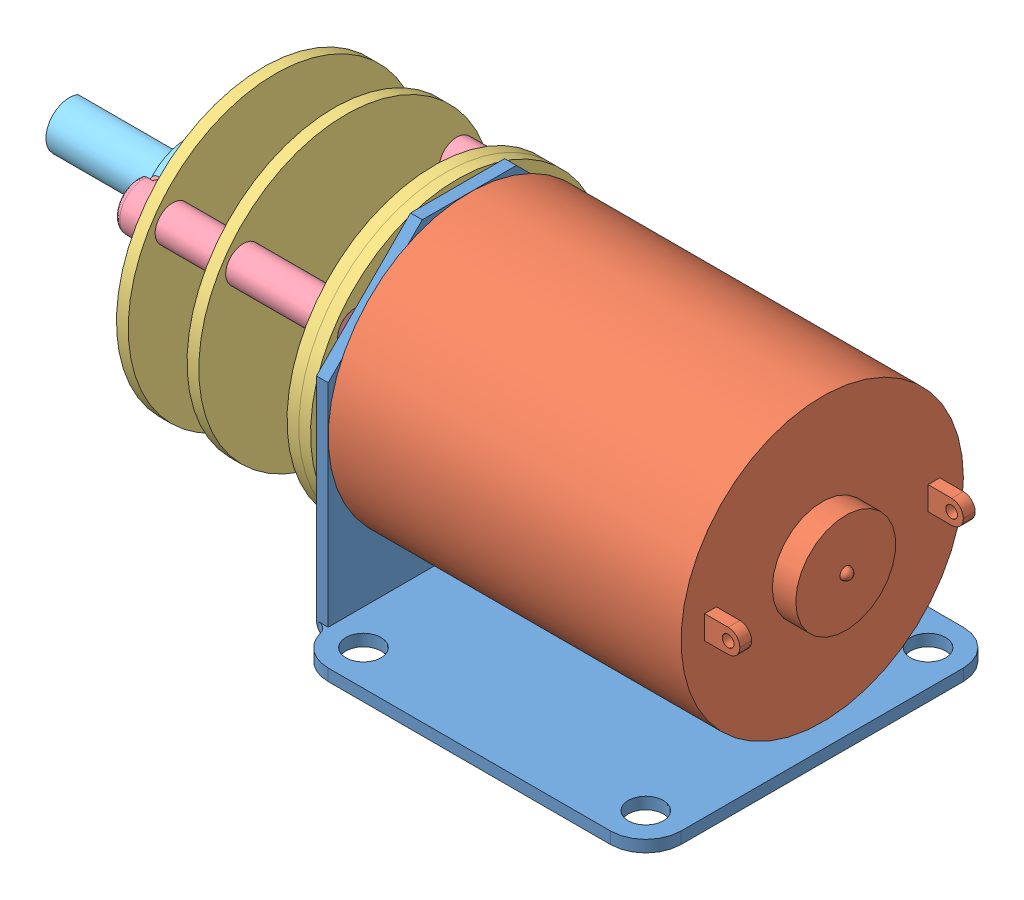
SolidWorks assembly MotorMFA, configuration Défaut. Lengths in mm.
Overall size (67 33.45 33.45).
10 component instances, 5 part files, 21 mates.
Components (placement in the parent):
- Square-1: Square [Défaut] at (-19.9694 1.8332 31) size (31 27 30)
- Body-1: Body [Défaut] at (11.0306 3.3332 31) size (33 24 24)
- Plate-1: Plate [Défaut] at (-20.9694 3.3332 31) x (1 0 0) z (0 0.898006 0.439983) size (1 25 25)
- Plate-2: Plate [Défaut] at (-21.9694 3.3332 31) x (1 0 0) z (0 0.898006 0.439983) size (1 25 25)
- Plate-3: Plate [Défaut] at (-30.4694 3.3332 31) x (1 0 0) z (0 0.898006 0.439983) size (1 25 25)
- Plate-4: Plate [Défaut] at (-36.4694 3.3332 31) x (1 0 0) z (0 0.898006 0.439983) size (1 25 25)
- Screw-4: Screw [Défaut] at (-19.9694 9.1891 39.7154) x (0 0.394119 0.91906) z (0 -0.91906 0.394119) size (4 18.53 4)
- Screw-5: Screw [Défaut] at (-19.9694 7.953 21.5709) x (0 0.311952 0.950098) z (0 -0.950098 0.311952) size (4 18.53 4)
- Screw-6: Screw [Défaut] at (-19.9694 -7.1425 31.7137) x (0 0.055415 0.998463) z (0 -0.998463 0.055415) size (4 18.53 4)
- MFARotor-1: MFARotor [Défaut] at (-36.4694 3.3332 31) x (-1 0 0) z (0 -0.886864 -0.46203) size (16.5 8 8)
Mates (geometry in assembly coordinates):
- Coaxiale1: concentric anti-aligned: cylinder of Square-1 through (11.0306 3.3332 31) axis (-1 0 0) radius 4; cylinder of Body-1 through (-18.9694 3.3332 31) axis (1 0 0) radius 12
- Coïncidente1: coincident anti-aligned: plane of Square-1 through (-18.9694 1.8332 31) normal (1 0 0); plane of Body-1 through (-18.9694 3.3332 31) normal (-1 0 0)
- Coaxiale2: concentric aligned: cylinder of Square-1 through (11.0306 3.3332 31) axis (-1 0 0) radius 4; cylinder of Plate-1 through (-19.9694 3.3332 31) axis (-1 0 0) radius 12.5
- Coïncidente2: coincident anti-aligned: plane of Square-1 through (-19.9694 1.8332 31) normal (-1 0 0); plane of Plate-1 through (-19.9694 3.3332 31) normal (1 0 0)
- Coaxiale3: concentric aligned: cylinder of Plate-1 through (-19.9694 3.3332 31) axis (-1 0 0) radius 12.5; cylinder of Plate-2 through (-20.9694 3.3332 31) axis (-1 0 0) radius 12.5
- Coaxiale4: concentric aligned: cylinder of Plate-2 through (-20.9694 3.3332 31) axis (-1 0 0) radius 12.5; cylinder of Plate-3 through (-29.4694 3.3332 31) axis (-1 0 0) radius 12.5
- Coaxiale5: concentric aligned: cylinder of Plate-3 through (-29.4694 3.3332 31) axis (-1 0 0) radius 12.5; cylinder of Plate-4 through (-35.4694 3.3332 31) axis (-1 0 0) radius 12.5
- Coaxiale6: concentric aligned: cylinder of Plate-1 through (-20.9694 7.953 21.5709) axis (1 0 0) radius 1.5; cylinder of Plate-2 through (-21.9694 7.953 21.5709) axis (1 0 0) radius 1.5
- Coaxiale7: concentric aligned: cylinder of Plate-2 through (-21.9694 7.953 21.5709) axis (1 0 0) radius 1.5; cylinder of Plate-3 through (-30.4694 7.953 21.5709) axis (1 0 0) radius 1.5
- Coaxiale8: concentric aligned: cylinder of Plate-3 through (-30.4694 7.953 21.5709) axis (1 0 0) radius 1.5; cylinder of Plate-4 through (-36.4694 7.953 21.5709) axis (1 0 0) radius 1.5
- Coïncidente4: coincident anti-aligned: plane of Plate-1 through (-20.9694 3.3332 31) normal (-1 0 0); plane of Plate-2 through (-20.9694 3.3332 31) normal (1 0 0)
- Distance1: distance = 5 mm anti-aligned: plane of Plate-3 through (-30.4694 3.3332 31) normal (-1 0 0); plane of Plate-4 through (-35.4694 3.3332 31) normal (1 0 0)
- Coïncidente10: coincident anti-aligned: plane of Plate-4 through (-36.4694 3.3332 31) normal (-1 0 0); plane of Screw-4 through (-36.4694 9.1891 39.7154) normal (1 0 0)
- Coïncidente11: coincident anti-aligned: plane of Plate-4 through (-36.4694 3.3332 31) normal (-1 0 0); plane of Screw-5 through (-36.4694 7.953 21.5709) normal (1 0 0)
- Coïncidente12: coincident anti-aligned: plane of Plate-4 through (-36.4694 3.3332 31) normal (-1 0 0); plane of Screw-6 through (-36.4694 -7.1425 31.7137) normal (1 0 0)
- Coaxiale12: concentric aligned: cylinder of Plate-4 through (-36.4694 -7.1425 31.7137) axis (1 0 0) radius 1.5; cylinder of Screw-6 through (-36.4694 -7.1425 31.7137) axis (1 0 0) radius 1.5
- Coaxiale13: concentric aligned: cylinder of Plate-4 through (-36.4694 7.953 21.5709) axis (1 0 0) radius 1.5; cylinder of Screw-5 through (-36.4694 7.953 21.5709) axis (1 0 0) radius 1.5
- Coaxiale14: concentric aligned: cylinder of Plate-4 through (-36.4694 9.1891 39.7154) axis (1 0 0) radius 1.5; cylinder of Screw-4 through (-36.4694 9.1891 39.7154) axis (1 0 0) radius 1.5
- Coïncidente13: coincident anti-aligned: plane of Square-1 through (-19.9694 1.8332 31) normal (-1 0 0); plane of Screw-4 through (-19.9694 9.1891 39.7154) normal (1 0 0)
- Coïncidente14: coincident aligned: plane of Plate-4 through (-36.4694 3.3332 31) normal (-1 0 0); circle of MFARotor-1
- Coaxiale15: concentric anti-aligned: cylinder of Plate-4 through (-35.4694 3.3332 31) axis (-1 0 0) radius 12.5; cylinder of MFARotor-1 through (-42.9694 3.3332 31) axis (1 0 0) radius 4
